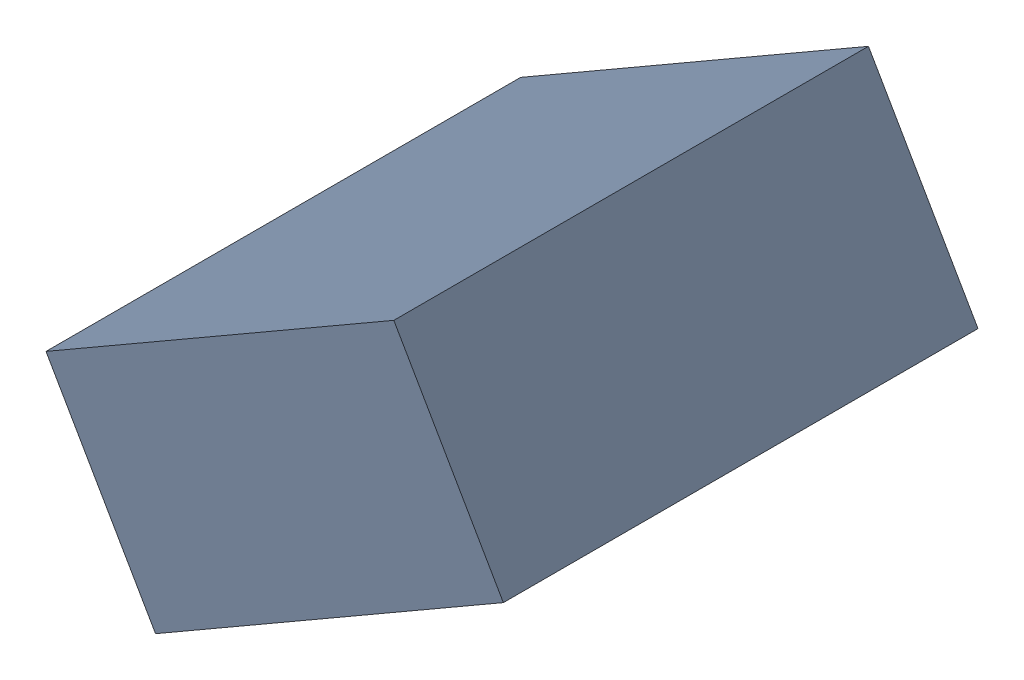
SolidWorks assembly C31_TDA2, configuration Standard. Lengths in mm.
Overall size (1.25 1.07 1.3).
2 component instances, 1 part files, 0 mates.
Components (placement in the parent):
- 885542920-1: 885542920 [Standard] at (50.7515 33.3311 0) size (1.25 1.07 1.3)
  - Extruded_24-1: Extruded_24 [Standard] at origin size (1.25 1.07 1.3)
